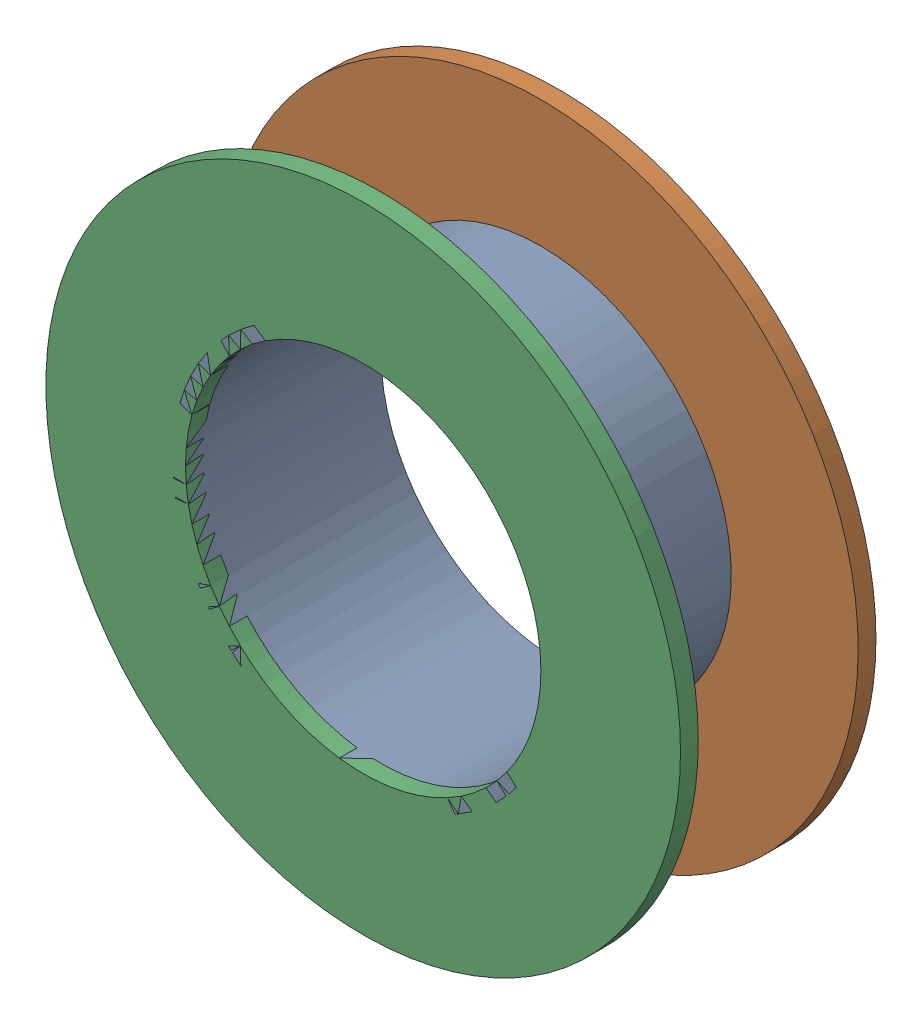
SolidWorks assembly Via (19.2mm,46.4mm) from Top Layer to Bottom Layer, configuration Predeterminado. Lengths in mm.
Overall size (1.27 1.27 0.39).
6 component instances, 2 part files, 0 mates.
Components (placement in the parent):
- Via Hole-1: Via Hole [Predeterminado] at (19.2 46.4 -0.4013) size (0.76 0.76 0.39)
  - Via Hole-Part-1-1: Via Hole-Part-1 [Predeterminado] at origin size (0.76 0.76 0.39)
- Via Top Layer-1: Via Top Layer [Predeterminado] at (19.2 46.4 -0.4013) size (1.27 1.27 0.04)
  - Via Top Layer-Part-1-1: Via Top Layer-Part-1 [Predeterminado] at origin size (1.27 1.27 0.04)
- Via Top Layer-2: Via Top Layer [Predeterminado] at (19.2 46.4 -0.0457) size (1.27 1.27 0.04)
  - Via Top Layer-Part-1-1: Via Top Layer-Part-1 [Predeterminado] at origin size (1.27 1.27 0.04)
